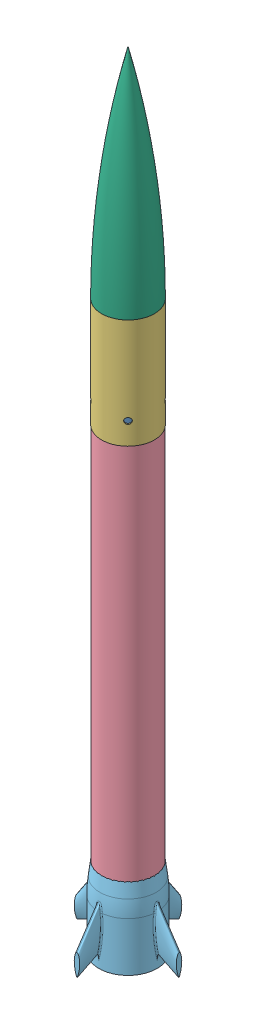
SolidWorks assembly Assem1, configuration Default. Lengths in mm.
Overall size (59.29 455.61 59.29).
7 component instances, 6 part files, 15 mates.
Components (placement in the parent):
- Avionics Bay-1: Avionics Bay [Default] at origin size (29 51.34 29)
- 9686T72_Routing Eyebolt with Nut - Not for Lifting-1: 9686T72_Routing Eyebolt with Nut - Not for Lifting [9686T72] at (-8.9356 -10.5079 0) x (0 0 -1) z (-1 0 0) size (14.68 43.63 8.51)
- 9686T72_Routing Eyebolt with Nut - Not for Lifting-2: 9686T72_Routing Eyebolt with Nut - Not for Lifting [9686T72] at (8.9356 -10.5079 0) x (0 0 -1) z (-1 0 0) size (14.68 43.63 8.51)
- Top Tube-1: Top Tube [Default] at (0 -244.475 0) size (30.7 63.5 30.7)
- Body Tube-1: Body Tube [Default] at (0 -244.475 0) size (30.7 254 30.7)
- Fin Can-1: Fin Can [Default] at (0 -247.65 -16.9375) x (0 0 -1) z (1 0 0) size (59.29 46.04 59.29)
- Nosecone-1: Nosecone [Default] at (0 50.8 0) x (-0.111725 0 -0.993739) z (0.993739 0 -0.111725) size (30.7 159.47 30.7)
Mates (geometry in assembly coordinates):
- Concentric1: concentric aligned: circle of Avionics Bay-1; circle of 9686T72_Routing Eyebolt with Nut - Not for Lifting-1
- Coincident3: coincident anti-aligned: plane of Avionics Bay-1 through (0 22.2343 0) normal (0 1 0); plane of 9686T72_Routing Eyebolt with Nut - Not for Lifting-1 through (-8.9356 22.2343 4.9127) normal (0 -1 0)
- Concentric2: concentric aligned: circle of Avionics Bay-1; circle of 9686T72_Routing Eyebolt with Nut - Not for Lifting-2
- Coincident5: coincident anti-aligned: plane of Avionics Bay-1 through (0 22.2343 0) normal (0 1 0); plane of 9686T72_Routing Eyebolt with Nut - Not for Lifting-2 through (8.9356 22.2343 4.9127) normal (0 -1 0)
- Concentric3: concentric anti-aligned: circle of Avionics Bay-1; cylinder of Top Tube-1 through (0 -244.475 0) axis (0 -1 0) radius 15.35
- Distance1: distance = 9.525 mm aligned: plane of Top Tube-1 through (0 9.525 0) normal (0 -1 0); plane of Avionics Bay-1 through (0 0 0) normal (0 -1 0)
- Coincident8: coincident anti-aligned: circle of Top Tube-1; plane of Body Tube-1 through (0 9.525 0) normal (0 1 0)
- Concentric5: concentric aligned: circle of Top Tube-1; circle of BodyTube-1
- Concentric6: concentric anti-aligned: circle of Top Tube-1; circle of Nosecone-1
- Coincident14: coincident anti-aligned: plane of Top Tube-1 through (0 73.025 0) normal (0 1 0); plane of Nosecone-1 through (0 73.025 0) normal (0 -1 0)
- Parallel2: parallel anti-aligned: plane of Avionics Bay-1 through (-13.4263 60.3343 0) normal (1 0 0); plane of 9686T72_Routing Eyebolt with Nut - Not for Lifting-1 through (-13.1901 25.5363 -2.4563) normal (-1 0 0)
- Parallel3: parallel anti-aligned: plane of 9686T72_Routing Eyebolt with Nut - Not for Lifting-1 through (-8.9356 25.5363 -4.9127) normal (-0.5 0 -0.866025); plane of 9686T72_Routing Eyebolt with Nut - Not for Lifting-2 through (8.9356 25.5363 4.9127) normal (0.5 0 0.866025)
- Coincident16: coincident: point of Fin Can-1
- Coincident17: coincident aligned: cylinder of Body Tube-1 through (0 -244.475 0) axis (0 -1 0) radius 15.35; circle of Fin-1
- Coincident18: coincident anti-aligned: circle of Body Tube-1; plane of Fin Can-1 through (0 -244.475 -16.9375) normal (0 1 0)
